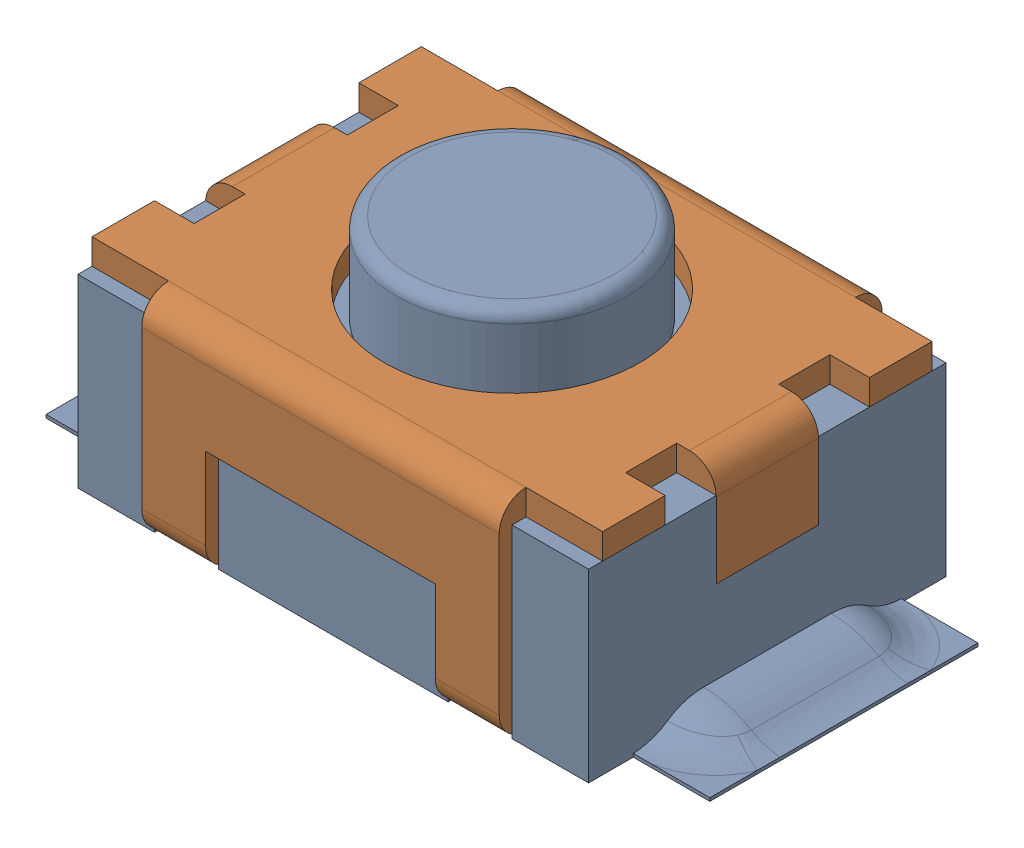
SolidWorks assembly reset_button, configuration Default. Lengths in mm.
Overall size (5.21 2.15 3).
2 component instances, 2 part files, 0 mates.
Components (placement in the parent):
- reset_core-1: reset_core [Default] at origin size (5.21 2.15 2.8)
- reset_shell-1: reset_shell [Default] at (0 1.65 0) x (0 0 1) z (-1 0 0) size (3 1.65 4)
